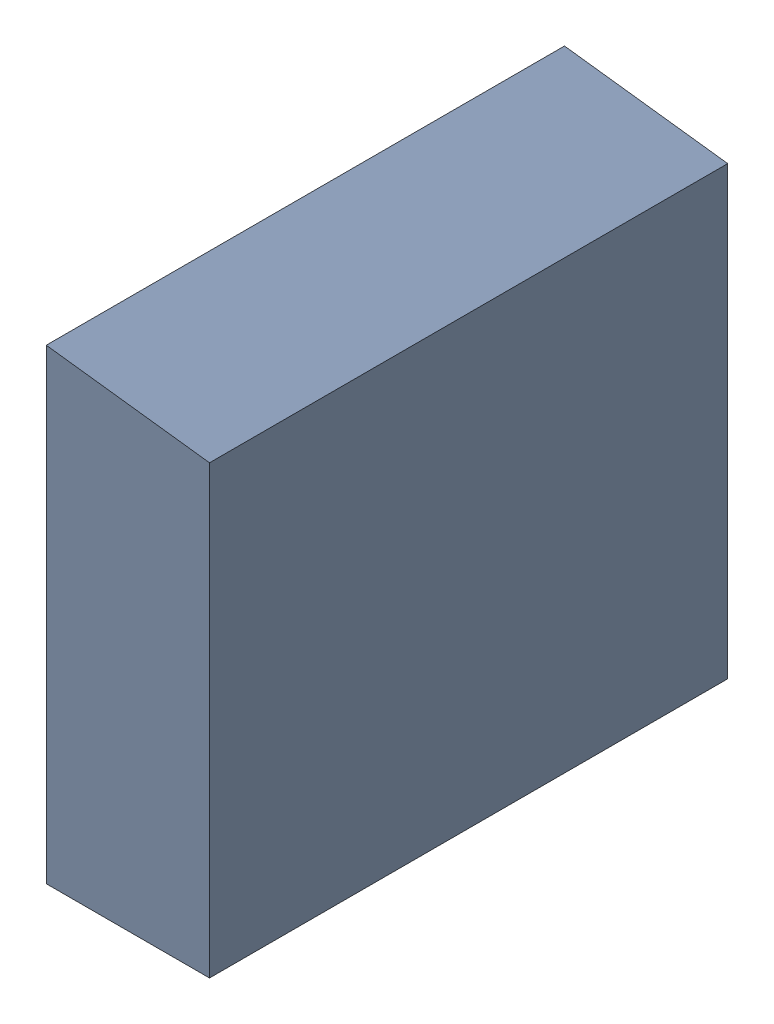
SolidWorks assembly SW3dPS-TO263-3S_Free-Models8, configuration Default. Lengths in mm.
Overall size (3.15 9 10).
2 component instances, 1 part files, 0 mates.
Components (placement in the parent):
- SW3dPS-TO263-3S_453496017-1: SW3dPS-TO263-3S_453496017 [Default] at (0 4.4 -4.9873) size (3.15 9 10)
  - SW3dPS-TO263-3S_Extruded18-1: SW3dPS-TO263-3S_Extruded18 [Default] at origin size (3.15 9 10)
